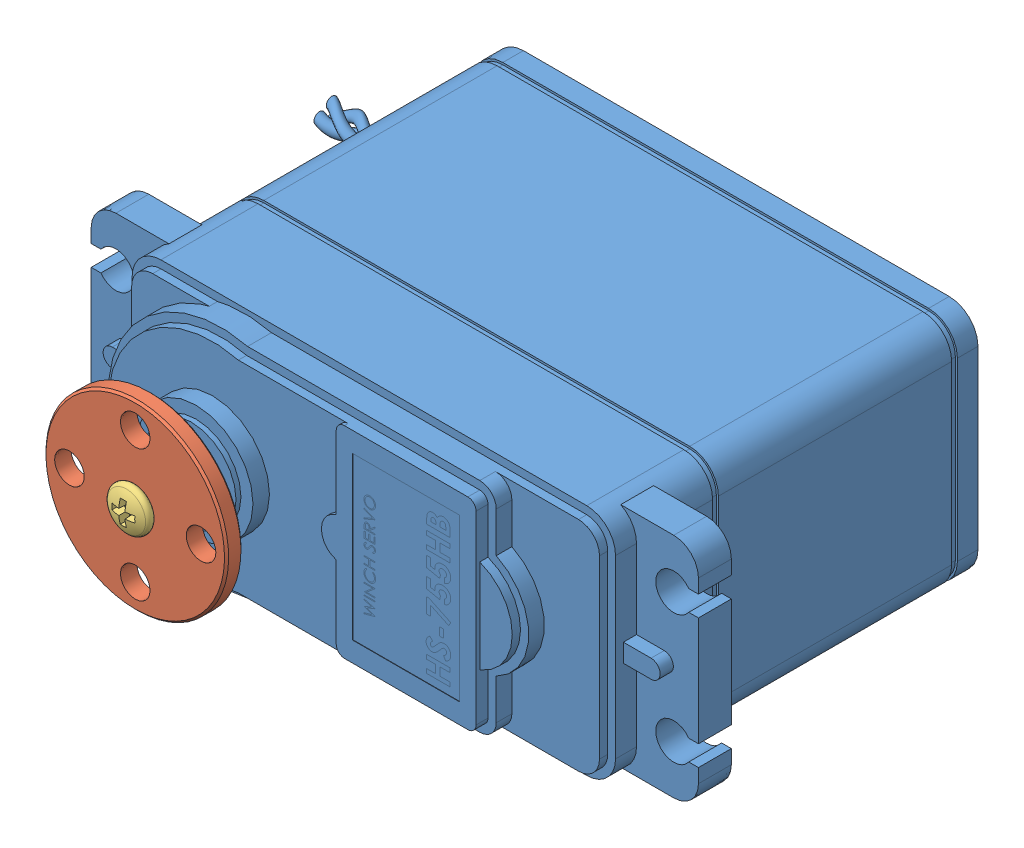
SolidWorks assembly Tetrix Servo Large 180° (with Horn), configuration Default. Lengths in mm.
Overall size (82.28 28.4 60.55).
4 component instances, 3 part files, 0 mates.
Components (placement in the parent):
- Tetrix Servo Large 180° Body-1: Tetrix Servo Large 180° Body [Default] at origin size (82.28 28.4 55.3)
- Tetrix Servo Horn (with Screw)-1: Tetrix Servo Horn (with Screw) [Default] at (-15.725 0 18.875) x (-1 0 0) z (0 1 0) size (22.2 11.58 22.2)
  - Tetrix Servo Horn-1: Tetrix Servo Horn [Default] at origin size (22.2 6.2 22.2)
  - Tetrix Servo Screw-1: Tetrix Servo Screw [Default] at (0 -3.6552 0) size (5.25 11.58 5.25)
